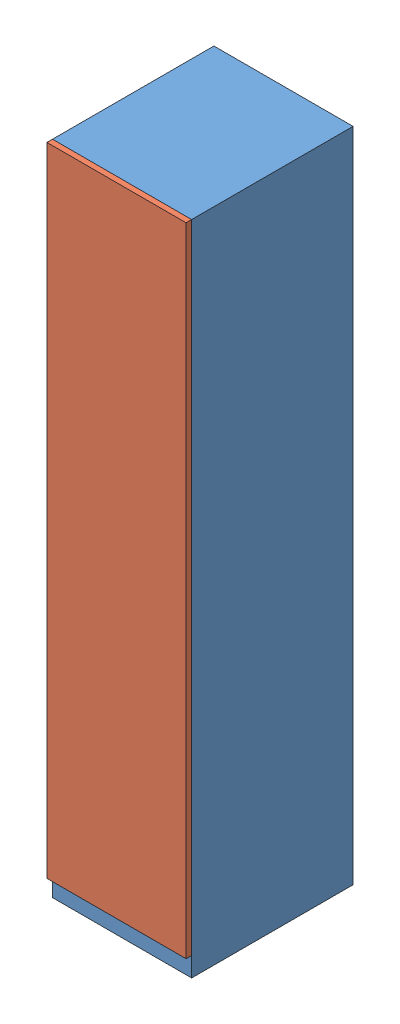
SolidWorks assembly PAX-Eingang, configuration Standard. Lengths in mm.
Overall size (500 2360 600).
7 component instances, 6 part files, 18 mates.
Components (placement in the parent):
- Pax-Korpus-Kleiderschrank-236-1: Pax-Korpus-Kleiderschrank-236 [Standard] at (-247.5936 -1124.7676 2360) size (500 2360 580)
- BALLSTAD-Tür-229-1: BALLSTAD-Tür-229 [Standard] at (-247.5936 90.2324 2650) size (500 2290 20)
- KOMPLEMENT-Regalbode-1: KOMPLEMENT-Regalbode [Standard] at (-247.5936 895.2324 2365) size (480 10 570)
- KOMPLEMENT-Kleiderstange-1: KOMPLEMENT-Kleiderstange [Standard] at (-487.5936 830.2324 2335) size (480 50 30)
- KOMPLEMENT-Regalbode-2: KOMPLEMENT-Regalbode [Standard] at (-247.5936 -434.7676 2365) size (480 10 570)
- KOMPLIMENT-Schublade-1: KOMPLIMENT-Schublade [Standard] at (-247.5936 -604.7676 2365) size (480 160 570)
- KOMPLEMENT-Netzdrahtkorb-1: KOMPLEMENT-Netzdrahtkorb [Standard] at (-247.5936 -904.7676 2365) size (480 160 570)
Mates (geometry in assembly coordinates):
- Deckungsgleich1: coincident: plane of Pax-Korpus-Kleiderschrank-236-1 through (-247.5936 1235.2324 2360) normal (0 1 0); plane of BALLSTAD-Tür-229-1 through (-497.5936 1235.2324 2670) normal (0 1 0)
- Deckungsgleich2: coincident: plane of Pax-Korpus-Kleiderschrank-236-1 through (-497.5936 -1114.7676 2650) normal (0 0 1); plane of BALLSTAD-Tür-229-1 through (-247.5936 90.2324 2650) normal (0 0 -1)
- Deckungsgleich3: coincident aligned: plane of Pax-Korpus-Kleiderschrank-236-1 through (-497.5936 -1114.7676 2650) normal (-1 0 0); plane of BALLSTAD-Tür-229-1 through (-497.5936 -1054.7676 2670) normal (-1 0 0)
- Deckungsgleich4: coincident anti-aligned: plane of Pax-Korpus-Kleiderschrank-236-1 through (-487.5936 1225.2324 2080) normal (0 0 1); plane of KOMPLEMENT-Regalbode-1 through (-487.5936 905.2324 2080) normal (0 0 -1)
- Deckungsgleich5: coincident anti-aligned: plane of Pax-Korpus-Kleiderschrank-236-1 through (-487.5936 1225.2324 2650) normal (1 0 0); plane of KOMPLEMENT-Regalbode-1 through (-487.5936 905.2324 2650) normal (-1 0 0)
- Abstand1: distance = 320 mm anti-aligned: plane of KOMPLEMENT-Regalbode-1 through (-247.5936 905.2324 2365) normal (0 1 0); plane of Pax-Korpus-Kleiderschrank-236-1 through (-247.5936 1225.2324 2360) normal (0 -1 0)
- Deckungsgleich7: coincident anti-aligned: plane of Pax-Korpus-Kleiderschrank-236-1 through (-487.5936 1225.2324 2650) normal (1 0 0); plane of KOMPLEMENT-Kleiderstange-1 through (-487.5936 830.2324 2335) normal (-1 0 0)
- Abstand2: distance = 50 mm anti-aligned: plane of KOMPLEMENT-Kleiderstange-1 through (-467.5936 845.2324 2320) normal (0 1 0); plane of KOMPLEMENT-Regalbode-1 through (-247.5936 895.2324 2365) normal (0 -1 0)
- Abstand3: distance = 300 mm aligned: plane of KOMPLEMENT-Kleiderstange-1 through (-467.5936 795.2324 2350) normal (0 0 1); plane of Pax-Korpus-Kleiderschrank-236-1 through (-497.5936 -1114.7676 2650) normal (0 0 1)
- Deckungsgleich10: coincident anti-aligned: plane of Pax-Korpus-Kleiderschrank-236-1 through (-487.5936 1225.2324 2080) normal (0 0 1); plane of KOMPLEMENT-Regalbode-2 through (-487.5936 -424.7676 2080) normal (0 0 -1)
- Deckungsgleich11: coincident anti-aligned: plane of Pax-Korpus-Kleiderschrank-236-1 through (-487.5936 1225.2324 2650) normal (1 0 0); plane of KOMPLEMENT-Regalbode-2 through (-487.5936 -424.7676 2650) normal (-1 0 0)
- Abstand4: distance = 1220 mm anti-aligned: plane of KOMPLEMENT-Kleiderstange-1 through (-467.5936 795.2324 2320) normal (0 -1 0); plane of KOMPLEMENT-Regalbode-2 through (-247.5936 -424.7676 2365) normal (0 1 0)
- Deckungsgleich13: coincident anti-aligned: plane of Pax-Korpus-Kleiderschrank-236-1 through (-487.5936 1225.2324 2080) normal (0 0 1); plane of KOMPLIMENT-Schublade-1 through (-487.5936 -594.7676 2080) normal (0 0 -1)
- Deckungsgleich14: coincident anti-aligned: plane of Pax-Korpus-Kleiderschrank-236-1 through (-487.5936 1225.2324 2650) normal (1 0 0); plane of KOMPLIMENT-Schublade-1 through (-487.5936 -594.7676 2650) normal (-1 0 0)
- Abstand5: distance = 10 mm anti-aligned: plane of KOMPLIMENT-Schublade-1 through (-247.5936 -444.7676 2365) normal (0 1 0); plane of KOMPLEMENT-Regalbode-2 through (-247.5936 -434.7676 2365) normal (0 -1 0)
- Deckungsgleich16: coincident: plane of Pax-Korpus-Kleiderschrank-236-1 through (-247.5936 -1064.7676 2360) normal (0 1 0); plane of KOMPLEMENT-Netzdrahtkorb-1 through (-247.5936 -1064.7676 2365) normal (0 -1 0)
- Deckungsgleich17: coincident: plane of Pax-Korpus-Kleiderschrank-236-1 through (-487.5936 1225.2324 2650) normal (1 0 0); line of KOMPLEMENT-Netzdrahtkorb-1 through (-487.5936 -904.7676 2080) axis (0 0 1)
- Deckungsgleich18: coincident: plane of Pax-Korpus-Kleiderschrank-236-1 through (-487.5936 1225.2324 2080) normal (0 0 1); line of KOMPLEMENT-Netzdrahtkorb-1 through (-7.5936 -904.7676 2080) axis (-1 0 0)
